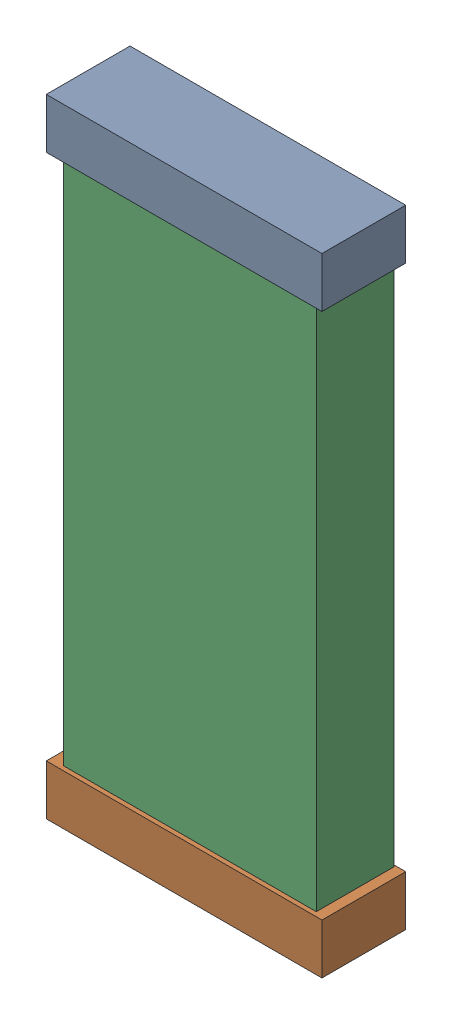
SolidWorks assembly PWR3, configuration Default. Lengths in mm.
Overall size (1.51 3.44 0.46).
6 component instances, 2 part files, 0 mates.
Components (placement in the parent):
- 744575856_4-1: 744575856_4 [Default] at (33.8999 62.419 -0.8715) size (1.51 0.28 0.46)
  - Extruded (27)-1: Extruded (27) [Default] at origin size (1.51 0.28 0.46)
- 744575856_5-1: 744575856_5 [Default] at (33.9 59.2565 -0.8715) size (1.51 0.28 0.46)
  - Extruded (27)-1: Extruded (27) [Default] at origin size (1.51 0.28 0.46)
- 710423568_2-1: 710423568_2 [Default] at (33.9079 60.8441 -0.8615) size (1.38 3.05 0.42)
  - Extruded (28)-1: Extruded (28) [Default] at origin size (1.38 3.05 0.42)
